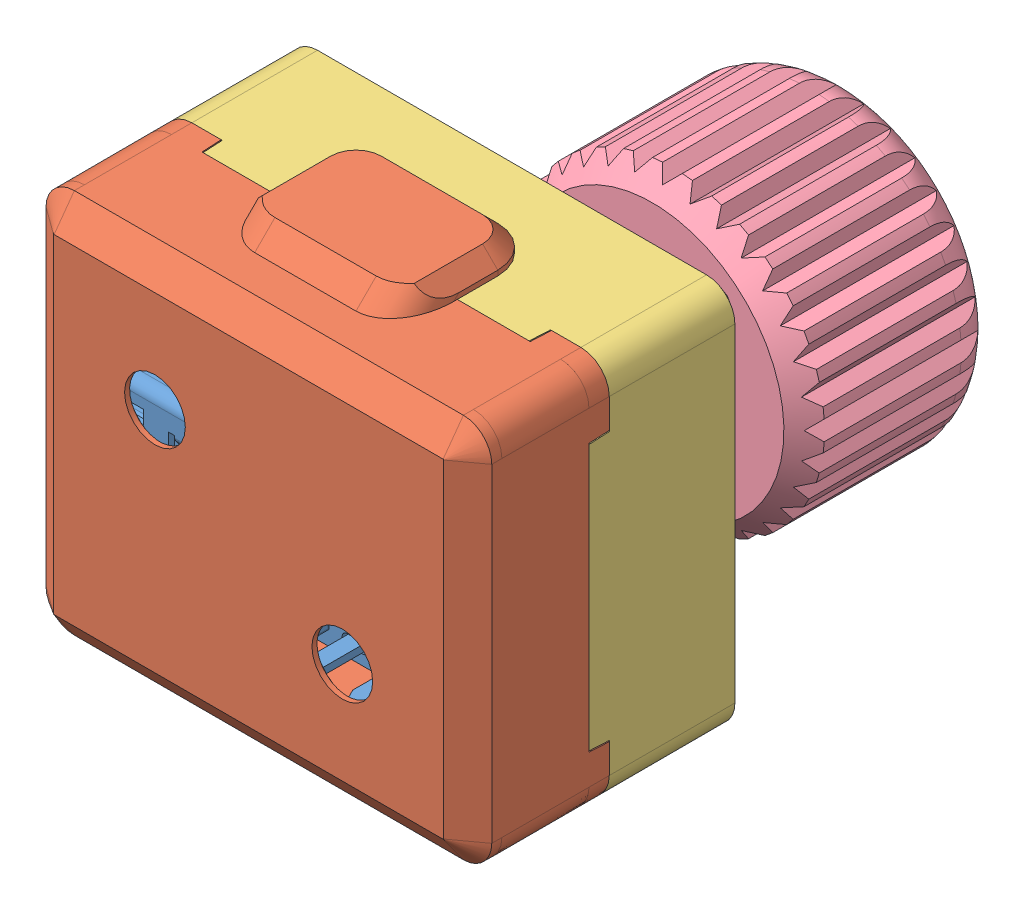
SolidWorks assembly enclosure2, configuration enclosure2. Lengths in mm.
Overall size (22 21 27.2).
4 component instances, 4 part files, 1 mates.
Components (placement in the parent):
- pcb-1: pcb [pcb] at origin size (20 16 21.2)
- lower-1: lower [lower] at origin size (22 21 9.8)
- upper-1: upper [upper] at origin size (22 19 8.76)
- knob-1: knob [knob] at (18.546 1.0524 2.44) x (-1 0 0) z (0 0 -1) size (15.21 15.21 9.75)
Mates (geometry in assembly coordinates):
- Coincident5: coincident anti-aligned: plane of pcb-1 through (14.5391 9.75 -7.0925) normal (0 1 0); plane of knob-1 through (18.546 9.75 -2.0871) normal (0 -1 0)
